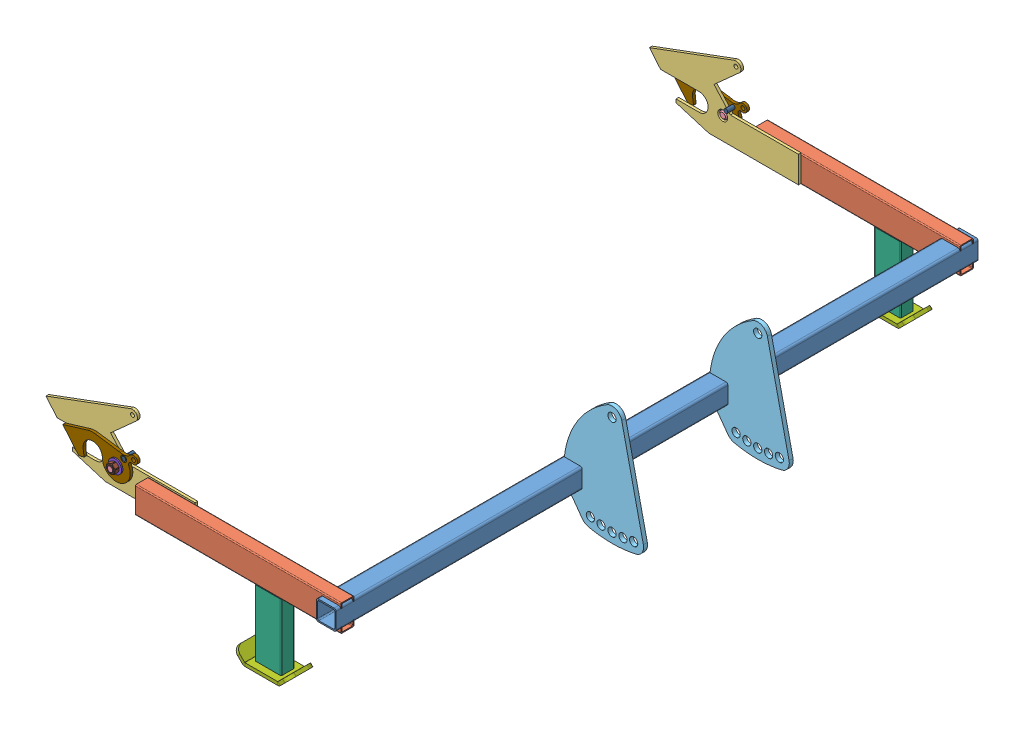
SolidWorks assembly ТП.016.10.00 - Рампа подъема навески, configuration 00. Lengths in mm.
Overall size (557.77 243.25 975.2).
31 component instances, 11 part files, 14 mates.
Components (placement in the parent):
- ТП.016.10.01.00 - Силовой элемент рампы-1: ТП.016.10.01.00 - Силовой элемент рампы [00] at origin size (557.77 243.25 975.2)
  - ТП.016.10.01.01.00 - Рама рампы-1: ТП.016.10.01.01.00 - Рама рампы [00] at origin size (465.09 116.43 969.2)
    - ТП.016.10.01.01.01 - Поперечина рампы-1: ТП.016.10.01.01.01 - Поперечина рампы [--] at origin size (30 30 969.2)
    - ТП.016.10.01.01.02.00 - Боковина рампы с вилкой-1: ТП.016.10.01.01.02.00 - Боковина рампы с вилкой [Правая] at (-15 -20.75 457.6) x (0 0 -1) z (1 0 0) size (24 116.43 465.09)
      - ТП.016.10.01.01.02.01 - Боковина рампы-1: ТП.016.10.01.01.02.01 - Боковина рампы [--] at origin size (20 40 310)
      - ТП.016.10.01.01.02.02.00 - Вилка замка-1: ТП.016.10.01.01.02.02.00 - Вилка замка [Правая] at (4 35 -360) x (0 0 1) z (-1 0 0) size (225.09 114.93 18)
        - ТП.016.10.01.01.02.02.01 - Вилка навески (Ст3 S4мм)-1: ТП.016.10.01.01.02.02.01 - Вилка навески (Ст3 S4мм) [Правая] at origin size (225.09 114.93 4)
        - ТП.016.10.01.01.02.02.02 - Ось вилки навески-1: ТП.016.10.01.01.02.02.02 - Ось вилки навески [--] at (35.5 0 0) x (0.984194 0.177092 0) z (0 0 1) size (12 12 18)
    - ТП.016.10.01.01.02.00 - Боковина рампы с вилкой-2: ТП.016.10.01.01.02.00 - Боковина рампы с вилкой [Левая] at (-15 -20.75 -477.6) x (0 0 -1) z (1 0 0) size (24 116.43 465.09)
      - ТП.016.10.01.01.02.01 - Боковина рампы-1: ТП.016.10.01.01.02.01 - Боковина рампы [--] at origin size (20 40 310)
      - ТП.016.10.01.01.02.02.00 - Вилка замка-1: ТП.016.10.01.01.02.02.00 - Вилка замка [Левая] at (-20 35 -360) x (0 0 1) z (-1 0 0) size (225.09 114.93 18)
        - ТП.016.10.01.01.02.02.01 - Вилка навески (Ст3 S4мм)-1: ТП.016.10.01.01.02.02.01 - Вилка навески (Ст3 S4мм) [Левая] at origin size (225.09 114.93 4)
        - ТП.016.10.01.01.02.02.02 - Ось вилки навески-1: ТП.016.10.01.01.02.02.02 - Ось вилки навески [--] at (35.5 0 4) x (0.984194 -0.177092 0) z (0 0 -1) size (12 12 18)
  - ТП.016.10.01.02 - Кронштейн рампы (Ст3 S-6мм)-1: ТП.016.10.01.02 - Кронштейн рампы (Ст3 S-6мм) [--] at (0 0 107) size (119.68 179.72 6)
  - ТП.016.10.01.02 - Кронштейн рампы (Ст3 S-6мм)-2: ТП.016.10.01.02 - Кронштейн рампы (Ст3 S-6мм) [--] at (0 0 -113) size (119.68 179.72 6)
  - ТП.016.10.01.03.00 - Нога-1: ТП.016.10.01.03.00 - Нога [00] at (-95 -120.75 467.6) size (85.36 105 40)
    - ТП.016.10.01.03.01 - Стойка-1: ТП.016.10.01.03.01 - Стойка [--] at origin size (40 100 20)
    - ТП.016.10.01.03.02 - Лыжа (Ст3 S-5мм)-1: ТП.016.10.01.03.02 - Лыжа (Ст3 S-5мм) [--] at origin size (85.36 19.14 40)
  - ТП.016.10.01.03.00 - Нога-2: ТП.016.10.01.03.00 - Нога [00] at (-95 -120.75 -467.6) size (85.36 105 40)
    - ТП.016.10.01.03.01 - Стойка-1: ТП.016.10.01.03.01 - Стойка [--] at origin size (40 100 20)
    - ТП.016.10.01.03.02 - Лыжа (Ст3 S-5мм)-1: ТП.016.10.01.03.02 - Лыжа (Ст3 S-5мм) [--] at origin size (85.36 19.14 40)
- ТП.016.10.02 - Втулка собачки навески-1: ТП.016.10.02 - Втулка собачки навески [--] at (-339.5 14.25 461.6) x (0.67216 -0.740406 0) z (0 0 1) size (20 20 6.5)
- ТП.016.10.03.00 - Собачка с фиксатором-3: ТП.016.10.03.00 - Собачка с фиксатором [Правая] at (-339.5 14.25 458.1) size (112.78 47.58 15)
  - ТП.016.10.03.01 - Собачка навески (Ст3 S-4мм)-1: ТП.016.10.03.01 - Собачка навески (Ст3 S-4мм) [Правая] at origin size (112.78 47.58 4)
  - ТП.016.10.03.02 - Фиксатор-курок-1: ТП.016.10.03.02 - Фиксатор-курок [--] at (11.1898 14.5852 4) x (0.982471 0.186418 0) z (-0.186418 0.982471 0) size (6 15 6)
- ТП.016.10.02 - Втулка собачки навески-2: ТП.016.10.02 - Втулка собачки навески [--] at (-339.5 14.25 -461.6) x (-0.183216 -0.983073 0) z (0 0 -1) size (20 20 6.5)
- ТП.016.10.03.00 - Собачка с фиксатором-4: ТП.016.10.03.00 - Собачка с фиксатором [Левая] at (-339.5 14.25 -462.1) size (112.78 47.58 15)
  - ТП.016.10.03.01 - Собачка навески (Ст3 S-4мм)-1: ТП.016.10.03.01 - Собачка навески (Ст3 S-4мм) [Левая] at origin size (112.78 47.58 4)
  - ТП.016.10.03.02 - Фиксатор-курок-1: ТП.016.10.03.02 - Фиксатор-курок [--] at (11.1898 14.5852 15) x (0.982471 0.186418 0) z (-0.186418 0.982471 0) size (6 15 6)
- Гайка (ГОСТ ISO 4032-2014)-1: Гайка (ГОСТ ISO 4032-2014) [Гайка М8 (ГОСТ ISO 4032)] at (-339.5 14.25 467.5) x (0.66902 0.743244 0) z (0 0 -1) size (13 14.38 6.8)
- Гайка (ГОСТ ISO 4032-2014)-2: Гайка (ГОСТ ISO 4032-2014) [Гайка М8 (ГОСТ ISO 4032)] at (-339.5 14.25 -467.5) x (0.97654 0.215336 0) z (0 0 1) size (13 14.38 6.8)
Mates (geometry in assembly coordinates):
- Концентричный1: concentric: cylinder of ТП.016.10.01.00 - Силовой элемент рампы-1/ТП.016.10.01.01.00 - Рама рампы-1/ТП.016.10.01.01.02.00 - Боковина рампы с вилкой-1/ТП.016.10.01.01.02.02.00 - Вилка замка-1/ТП.016.10.01.01.02.02.02 - Ось вилки навески-1 through (-339.5 14.25 453.6) axis (0 0 -1) radius 4.5; cylinder of ТП.016.10.02 - Втулка собачки навески-1 through (-339.5 14.25 453.6) axis (0 0 -1) radius 4.5
- Совпадение1: coincident: plane of ТП.016.10.01.00 - Силовой элемент рампы-1/ТП.016.10.01.01.00 - Рама рампы-1/ТП.016.10.01.01.02.00 - Боковина рампы с вилкой-1/ТП.016.10.01.01.02.02.00 - Вилка замка-1/ТП.016.10.01.01.02.02.01 - Вилка навески (Ст3 S4мм)-1 through (-319.5 88.1849 457.6) normal (0 0 1); plane of ТП.016.10.02 - Втулка собачки навески-1 through (-336.1682 17.2747 457.6) normal (0 0 -1)
- Концентричный2: concentric: cylinder of ТП.016.10.02 - Втулка собачки навески-1 through (-339.5 14.25 453.6) axis (0 0 -1) radius 6.25; cylinder of ТП.016.10.03.00 - Собачка с фиксатором-3/ТП.016.10.03.01 - Собачка навески (Ст3 S-4мм)-1 through (-339.5 14.25 462.1) axis (0 0 -1) radius 6.5
- Совпадение2: coincident: plane of ТП.016.10.02 - Втулка собачки навески-1 through (-334.8725 18.451 462.1) normal (0 0 -1); plane of ТП.016.10.03.00 - Собачка с фиксатором-3/ТП.016.10.03.01 - Собачка навески (Ст3 S-4мм)-1 through (-375 14.25 462.1) normal (0 0 1)
- Концентричный3: concentric: circle of ТП.016.10.01.00 - Силовой элемент рампы-1/ТП.016.10.01.01.00 - Рама рампы-1/ТП.016.10.01.01.02.00 - Боковина рампы с вилкой-1/ТП.016.10.01.01.02.02.00 - Вилка замка-1/ТП.016.10.01.01.02.02.01 - Вилка навески (Ст3 S4мм)-1; cylinder of ТП.016.10.03.00 - Собачка с фиксатором-3/ТП.016.10.03.01 - Собачка навески (Ст3 S-4мм)-1 through (-375 14.25 462.1) axis (0 0 -1) radius 14.5
- Концентричный4: concentric: cylinder of ТП.016.10.01.00 - Силовой элемент рампы-1/ТП.016.10.01.01.00 - Рама рампы-1/ТП.016.10.01.01.02.00 - Боковина рампы с вилкой-2/ТП.016.10.01.01.02.02.00 - Вилка замка-1/ТП.016.10.01.01.02.02.02 - Ось вилки навески-1 through (-339.5 14.25 -453.6) axis (0 0 1) radius 4.5; cylinder of ТП.016.10.02 - Втулка собачки навески-2 through (-339.5 14.25 -453.6) axis (0 0 1) radius 4.5
- Совпадение3: coincident: plane of ТП.016.10.01.00 - Силовой элемент рампы-1/ТП.016.10.01.01.00 - Рама рампы-1/ТП.016.10.01.01.02.00 - Боковина рампы с вилкой-2/ТП.016.10.01.01.02.02.00 - Вилка замка-1/ТП.016.10.01.01.02.02.01 - Вилка навески (Ст3 S4мм)-1 through (-319.5 88.1849 -457.6) normal (0 0 -1); plane of ТП.016.10.02 - Втулка собачки навески-2 through (-343.9238 15.0745 -457.6) normal (0 0 1)
- Совпадение4: coincident: plane of ТП.016.10.02 - Втулка собачки навески-2 through (-345.6442 15.3951 -462.1) normal (0 0 1); plane of ТП.016.10.03.00 - Собачка с фиксатором-4/ТП.016.10.03.01 - Собачка навески (Ст3 S-4мм)-1 through (-375 14.25 -462.1) normal (0 0 -1)
- Концентричный5: concentric: cylinder of ТП.016.10.02 - Втулка собачки навески-2 through (-339.5 14.25 -453.6) axis (0 0 1) radius 6.25; cylinder of ТП.016.10.03.00 - Собачка с фиксатором-4/ТП.016.10.03.01 - Собачка навески (Ст3 S-4мм)-1 through (-339.5 14.25 -458.1) axis (0 0 -1) radius 6.5
- Концентричный6: concentric: cylinder of ТП.016.10.01.00 - Силовой элемент рампы-1/ТП.016.10.01.01.00 - Рама рампы-1/ТП.016.10.01.01.02.00 - Боковина рампы с вилкой-2/ТП.016.10.01.01.02.02.00 - Вилка замка-1/ТП.016.10.01.01.02.02.01 - Вилка навески (Ст3 S4мм)-1 through (-375 14.25 -453.6) axis (0 0 -1) radius 13.5; cylinder of ТП.016.10.03.00 - Собачка с фиксатором-4/ТП.016.10.03.01 - Собачка навески (Ст3 S-4мм)-1 through (-375 14.25 -458.1) axis (0 0 -1) radius 14.5
- Совпадение5: coincident: plane of ТП.016.10.02 - Втулка собачки навески-1 through (-332.0959 20.9716 464.1) normal (0 0 1); plane of Гайка (ГОСТ ISO 4032-2014)-1 through (-335.1892 10.3697 464.1) normal (0 0 -1)
- Концентричный7: concentric: cylinder of ТП.016.10.01.00 - Силовой элемент рампы-1/ТП.016.10.01.01.00 - Рама рампы-1/ТП.016.10.01.01.02.00 - Боковина рампы с вилкой-1/ТП.016.10.01.01.02.02.00 - Вилка замка-1/ТП.016.10.01.01.02.02.02 - Ось вилки навески-1 through (-339.5 14.25 453.6) axis (0 0 -1) radius 4; cylinder of Гайка (ГОСТ ISO 4032-2014)-1 through (-339.5 14.25 314.7598) axis (0 0 -1) radius 2.9175
- Совпадение6: coincident: plane of ТП.016.10.02 - Втулка собачки навески-2 through (-349.3307 16.0822 -464.1) normal (0 0 -1); plane of Гайка (ГОСТ ISO 4032-2014)-2 through (-340.7489 19.9139 -464.1) normal (0 0 1)
- Концентричный8: concentric: cylinder of ТП.016.10.01.00 - Силовой элемент рампы-1/ТП.016.10.01.01.00 - Рама рампы-1/ТП.016.10.01.01.02.00 - Боковина рампы с вилкой-2/ТП.016.10.01.01.02.02.00 - Вилка замка-1/ТП.016.10.01.01.02.02.02 - Ось вилки навески-1 through (-339.5 14.25 -453.6) axis (0 0 1) radius 4; cylinder of Гайка (ГОСТ ISO 4032-2014)-2 through (-339.5 14.25 -314.7598) axis (0 0 1) radius 2.9175
